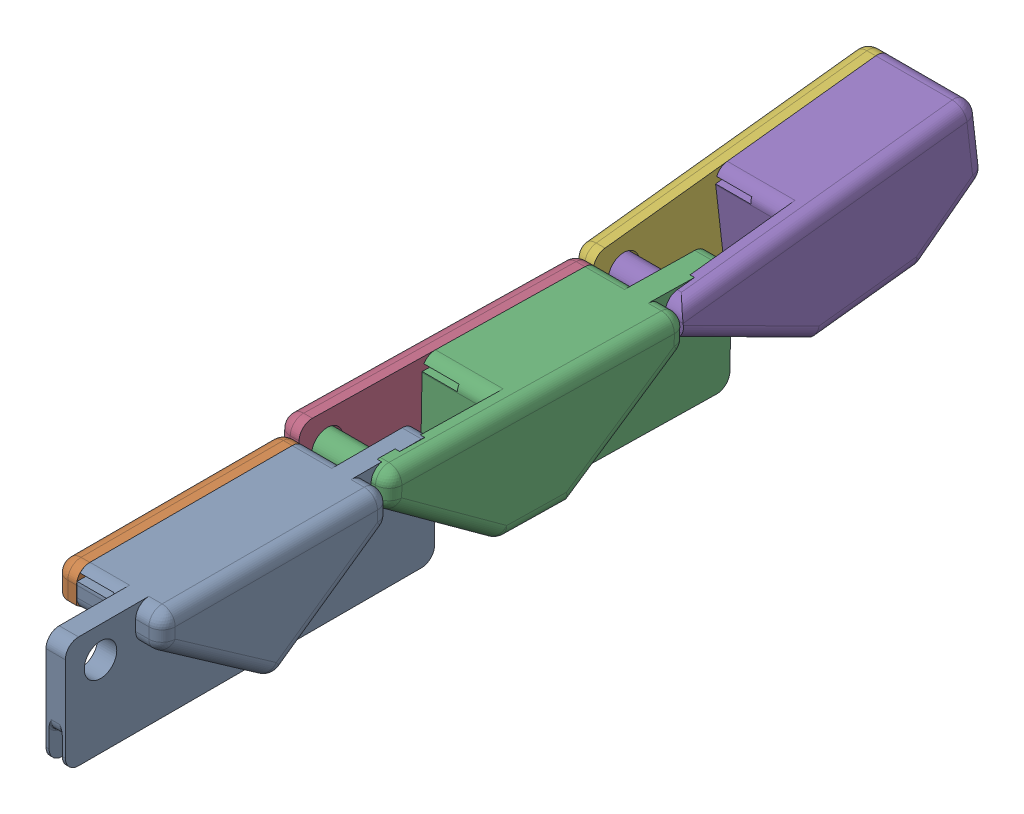
SolidWorks assembly pointer and ring assembly, configuration Default. Lengths in mm.
Overall size (14.72 16.5 104.34).
6 component instances, 6 part files, 10 mates.
Components (placement in the parent):
- first_knuckle_michelle_right_2 and 4-1: first_knuckle_michelle_right_2 and 4 [Default] at (33.5621 1.996 20.4025) size (11.1 12.7 42)
- first_knuckle_michelle_Left_2 and 4-1: first_knuckle_michelle_Left_2 and 4 [Default] at (2.2839 1.996 23.3141) x (0 0 -1) z (1 0 0) size (26.02 12.36 2.5)
- second_knuckle_michelle_R_2 and 4-1: second_knuckle_michelle_R_2 and 4 [Default] at (32.0541 1.7203 -14.1772) x (1 0 0) z (0 0.018231 0.999834) size (11.6 12.7 42)
- second_knuckle_michelle_L_2 and 4-1: second_knuckle_michelle_L_2 and 4 [Default] at (0.7759 2.6279 -16.9546) x (0 -0.018231 -0.999834) z (0 -0.999834 0.018231) size (34 2.5 12.7)
- last_knuckle_michelleR_2 and 4-1: last_knuckle_michelleR_2 and 4 [Default] at (41.2145 1.3735 -34.5098) x (1 0 0) z (0 -0.11433 0.993443) size (11.6 12.7 34)
- last_knuckle_michelle_L_2 and 4-1: last_knuckle_michelle_L_2 and 4 [Default] at (-0.2321 4.4287 -52.6765) x (0 0.11433 -0.993443) z (0 -0.993443 -0.11433) size (34 2.5 12.7)
Mates (geometry in assembly coordinates):
- Concentric1: concentric aligned: circle of first_knuckle_michelle_right_2 and 4-1; circle of first_knuckle_michelle_Left_2 and 4-1
- Coincident1: coincident aligned: line of first_knuckle_michelle_right_2 and 4-1 through (4.7839 14.696 6.3583) axis (0 0 1); line of first_knuckle_michelle_Left_2 and 4-1 through (4.7839 14.696 6.3583) axis (0 0 1)
- Concentric2: concentric aligned: circle of second_knuckle_michelle_R_2 and 4-1; circle of second_knuckle_michelle_L_2 and 4-1
- Coincident2: coincident aligned: line of second_knuckle_michelle_R_2 and 4-1 through (3.2759 14.1621 -28.4506) axis (0 0.018231 0.999834); line of second_knuckle_michelle_L_2 and 4-1 through (3.2759 14.1621 -28.4506) axis (0 0.018231 0.999834)
- Concentric3: concentric anti-aligned: circle of first_knuckle_michelle_right_2 and 4-1; circle of second_knuckle_michelle_R_2 and 4-1
- Distance1: distance = 0.508 mm: line of second_knuckle_michelle_R_2 and 4-1 through (10.9759 14.4721 -11.4534) axis (0 0.018231 0.999834); line of first_knuckle_michelle_right_2 and 4-1 through (11.4839 14.696 6.3583) axis (0 0 -1)
- Concentric4: concentric anti-aligned: circle of last_knuckle_michelleR_2 and 4-1; circle of last_knuckle_michelle_L_2 and 4-1
- Coincident4: coincident aligned: line of last_knuckle_michelleR_2 and 4-1 through (2.2679 17.3836 -62.5439) axis (0 -0.11433 0.993443); line of last_knuckle_michelle_L_2 and 4-1 through (2.2679 17.3836 -62.5439) axis (0 -0.11433 0.993443)
- Concentric5: concentric anti-aligned: circle of second_knuckle_michelle_R_2 and 4-1; circle of last_knuckle_michelleR_2 and 4-1
- Distance2: distance = 0.508 mm: line of last_knuckle_michelleR_2 and 4-1 through (9.9679 15.44 -45.6554) axis (0 -0.11433 0.993443); line of second_knuckle_michelle_R_2 and 4-1 through (10.4759 14.1621 -28.4506) axis (0 -0.018231 -0.999834)
